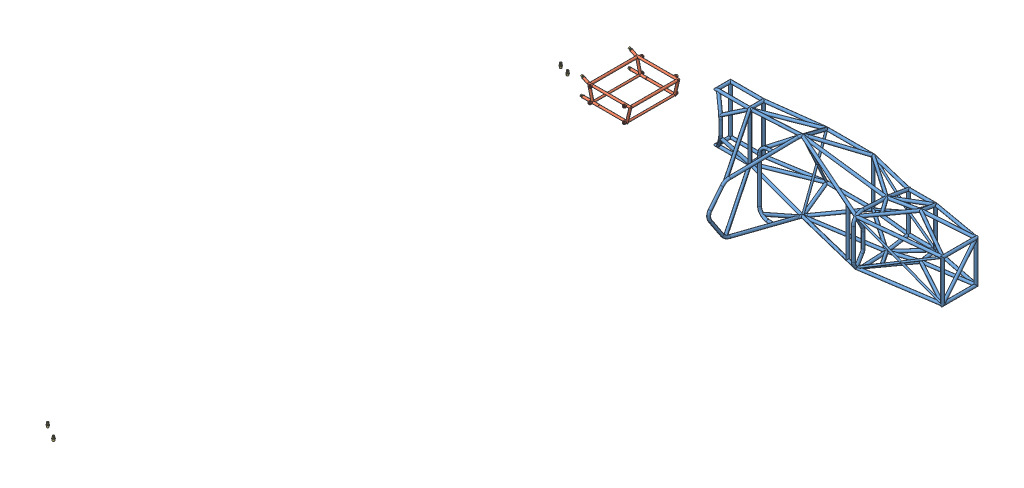
SolidWorks assembly Assem2, configuration Default. Lengths in mm.
Overall size (5311.04 2771.64 3317.3).
10 component instances, 3 part files, 9 mates.
Components (placement in the parent):
- Frame-1: Frame [Default<As Machined>] at (622.765 70.5614 -614.9803) size (2330.4 661.74 1035.4)
- Model1-1: Model1 [Default] at (-1744.5113 -73.5245 -494.9832) size (438.86 169.73 491.92)
- Plug-1: Plug [Default] at (-1985.5202 78.9925 -63.0632) x (0.429318 0.903153 0) z (0 0 1) size (23 40 23)
- Plug-2: Plug [Default] at (-1990.3105 -73.5245 -63.0632) x (0 1 0) z (0 0 1) size (23 40 23)
- Plug-3: Plug [Default] at (-1990.3105 -73.5245 -494.9832) x (0 1 0) z (0 0 1) size (23 40 23)
- Plug-4: Plug [Default] at (-1895.1907 275.5653 168.6197) size (23 40 23)
- Plug-5: Plug [Default] at (-1985.5202 78.9925 -494.9832) x (0.429318 0.903153 0) z (0 0 1) size (23 40 23)
- Plug-6: Plug [Default] at (-1918.1457 342.5689 207.9247) size (23 40 23)
- Plug-7: Plug [Default] at (-4059.0796 -2293.6283 2709.4683) size (23 40 23)
- Plug-8: Plug [Default] at (-3984.0673 -2350.5713 2733.1208) size (23 40 23)
Mates (geometry in assembly coordinates):
- Concentric1: concentric anti-aligned: cylinder of Model1-1 through (-1985.3105 -73.5245 -63.0632) axis (1 0 0) radius 8.3; cylinder of Plug-2 through (-1970.3105 -73.5245 -63.0632) axis (-1 0 0) radius 8.8
- Concentric2: concentric anti-aligned: cylinder of Model1-1 through (-1985.3105 -73.5245 -63.0632) axis (1 0 0) radius 8.3; cylinder of Plug-2 through (-1970.3105 -73.5245 -63.0632) axis (-1 0 0) radius 8.8
- Coincident1: coincident anti-aligned: plane of Model1-1 through (-1985.3105 -73.5245 -63.0632) normal (-1 0 0); plane of Plug-2 through (-1985.3105 -73.5245 -63.0632) normal (1 0 0)
- Concentric3: concentric anti-aligned: cylinder of Model1-1 through (-1985.3105 -73.5245 -494.9832) axis (1 0 0) radius 8.3; cylinder of Plug-3 through (-1970.3105 -73.5245 -494.9832) axis (-1 0 0) radius 8.8
- Coincident2: coincident anti-aligned: plane of Model1-1 through (-1985.3105 -73.5245 -494.9832) normal (-1 0 0); plane of Plug-3 through (-1985.3105 -73.5245 -494.9832) normal (1 0 0)
- Concentric4: concentric aligned: cylinder of Model1-1 through (-1931.5113 53.3191 -63.0632) axis (-0.903153 0.429318 0) radius 8.03; cylinder of Plug-1 through (-1967.4571 70.4061 -63.0632) axis (-0.903153 0.429318 0) radius 8.8
- Coincident6: coincident anti-aligned: plane of Model1-1 through (-1981.0044 76.8459 -63.0632) normal (-0.903153 0.429318 0); plane of Plug-1 through (-1981.0044 76.8459 -63.0632) normal (0.903153 -0.429318 0)
- Concentric5: concentric aligned: cylinder of Model1-1 through (-1931.5113 53.3191 -494.9832) axis (-0.903153 0.429318 0) radius 8.03; cylinder of Plug-5 through (-1967.4571 70.4061 -494.9832) axis (-0.903153 0.429318 0) radius 8.8
- Coincident7: coincident anti-aligned: plane of Model1-1 through (-1981.0044 76.8459 -494.9832) normal (-0.903153 0.429318 0); plane of Plug-5 through (-1981.0044 76.8459 -494.9832) normal (0.903153 -0.429318 0)
